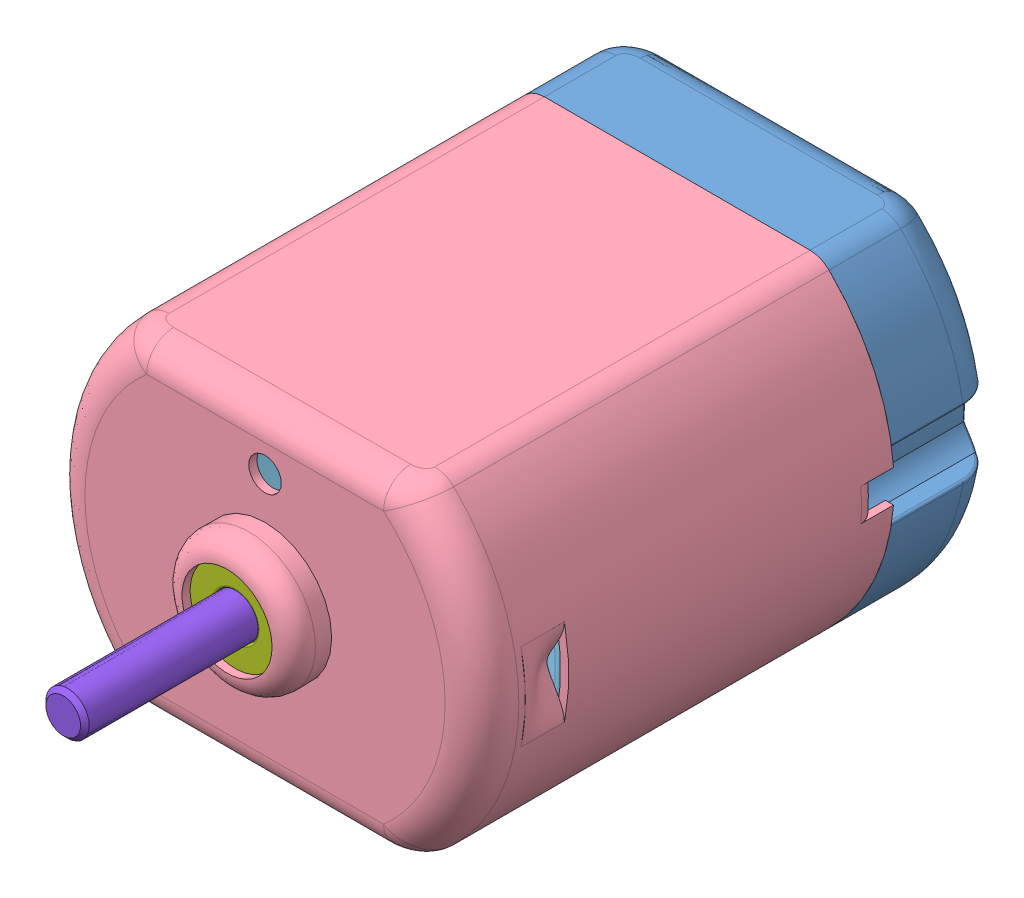
SolidWorks assembly Complete DC-Motor Assembly, configuration Default. Lengths in mm.
Overall size (20.01 18.13 38).
10 component instances, 8 part files, 19 mates.
Components (placement in the parent):
- DC Motor Cover-1: DC Motor Cover [Default] at origin size (19.93 15 10)
- Bearing 1-1: Bearing 1 [Default] at (0 0 -1) x (0.996254 0.086472 0) z (0 0 1) size (6 6 3)
- Brush-1: Brush [Default] at (-4.49 -2.335 4.9) x (-1 0 0) z (0 0 -1) size (7.84 5.94 7)
- Brush-2: Brush [Default] at (4.49 2.335 4.9) x (1 0 0) z (0 0 -1) size (7.84 5.94 7)
- DC Motor Case-1: DC Motor Case [Default] at (0 0 14.5) size (20.01 15 20.75)
- Magnet-1: Magnet [Default] at (-1.6142 -0.001 8) x (-1 -0.00062 0) z (0 0 1) size (4.99 13.78 12)
- Magnet-2: Magnet [Default] at (1.6142 -0.001 20) x (1 -0.00062 0) z (0 0 -1) size (4.99 13.78 12)
- Separator-1: Separator [Default] at (0.1985 -6.125 7.875) x (1 0 0) z (0 0 -1) size (9 1 15.75)
- Bearing 2-1: Bearing 2 [Default] at (0 0 25.375) x (-0.303258 -0.952909 0) z (0 0 -1) size (5.5 5.5 1.75)
- Rotor-1: Rotor [Default] at (0 0 14.3) x (0.778044 0.62821 0) z (0 0 1) size (13 12.8 38)
Mates (geometry in assembly coordinates):
- Concentric1: concentric: cylinder of DC Motor Cover-1 through (0 0 -1) axis (0 0 1) radius 3; cylinder of Bearing 1-1 through (0 0 2) axis (0 0 -1) radius 3
- Coincident1: coincident: plane of DC Motor Cover-1 through (0 0 -1) normal (0 0 1); plane of Bearing 1-1 through (0 0 -1) normal (0 0 -1)
- Coincident2: coincident: plane of DC Motor Cover-1 through (-5.6 -1.4 8) normal (1 0 0); plane of Brush-1 through (-5.6 -2.335 2.4) normal (-1 0 0)
- Width1: width: plane of Brush-1 through (-5.6 1.335 -2.1) normal (0 1 0); plane of Brush-1 through (-5.2 -1.335 2.4) normal (0 -1 0); plane of DC Motor Cover-1 through (-5.6 -1.4 8) normal (0 1 0); plane of DC Motor Cover-1 through (-5.6 1.4 8) normal (0 -1 0)
- Concentric2: concentric: cylinder of DC Motor Cover-1 through (0 0 6.5) axis (0 0 -1) radius 9.62; cylinder of DC Motor Case-1 through (0 0 24) axis (0 0 -1) radius 9.625
- Coincident3: coincident: plane of DC Motor Cover-1 through (0 -7.5 5) normal (0 -1 0); plane of DC Motor Case-1 through (-6.6144 -7.5 24) normal (0 -1 0)
- Coincident4: coincident: plane of DC Motor Cover-1 through (0 7.5 5) normal (0 1 0); plane of DC Motor Case-1 through (-6.6144 7.5 24) normal (0 1 0)
- Concentric3: concentric: cylinder of DC Motor Case-1 through (0 0 24) axis (0 0 -1) radius 9.625; cylinder of Magnet-1 through (0 0 20) axis (0 0 -1) radius 9.63
- Coincident5: coincident: plane of DC Motor Case-1 through (-9.0241 0.1658 20) normal (0 0 -1); plane of Magnet-1 through (0 0 20) normal (0 0 1)
- Coincident7: coincident: line of DC Motor Case-1 through (-4.7918 -6.5266 14) axis (0 0 1); plane of Magnet-1 through (-4.8739 -6.883 20) normal (0.974509 -0.224347 0)
- Coincident8: coincident: plane of DC Motor Case-1 through (-6.6144 -7.125 24) normal (0 1 0); plane of Separator-1 through (-3.7515 -7.125 20.875) normal (0 -1 0)
- Coincident9: coincident: plane of DC Motor Case-1 through (0 0 23.625) normal (0 0 -1); plane of Separator-1 through (-1.7515 -6.125 23.625) normal (0 0 1)
- Width2: width: plane of Separator-1 through (4.5015 -6.125 20.875) normal (1 0 0); plane of Separator-1 through (-4.5015 -6.125 20.875) normal (-1 0 0); plane of Magnet-2 through (4.8739 -6.883 8) normal (-0.974509 -0.224347 0); plane of Magnet-1 through (-4.8739 -6.883 20) normal (0.974509 -0.224347 0)
- Concentric4: concentric: cylinder of DC Motor Case-1 through (0 0 25.75) axis (0 0 1) radius 2.075; cylinder of Bearing 2-1 through (0 0 23.625) axis (0 0 1) radius 2.75
- Coincident10: coincident: circle of DC Motor Case-1; plane of Bearing 2-1 through (0 0 25.375) normal (0 0 1)
- Concentric5: concentric: cylinder of Bearing 2-1 through (0 0 23.625) axis (0 0 1) radius 1; cylinder of Rotor-1 through (0 0 -4.7) axis (0 0 1) radius 1
- Coincident11: coincident: plane of Bearing 1-1 through (0 0 2) normal (0 0 1); plane of Rotor-1 through (-1.1282 -0.9109 2) normal (0 0 -1)
- Width3: width: plane of Brush-1 through (-3.12 -2.835 4.9) normal (0 0 1); plane of Brush-1 through (-3.38 -2.835 2.4) normal (0 0 -1); plane of Rotor-1 through (0 0 2.25) normal (0 0 -1); plane of Rotor-1 through (0.5189 -1.6375 5.05) normal (0 0 -1)
- Coincident12: coincident: plane of DC Motor Cover-1 through (0 0 5) normal (0 0 1); plane of DC Motor Case-1 through (0 0 5) normal (0 0 -1)
